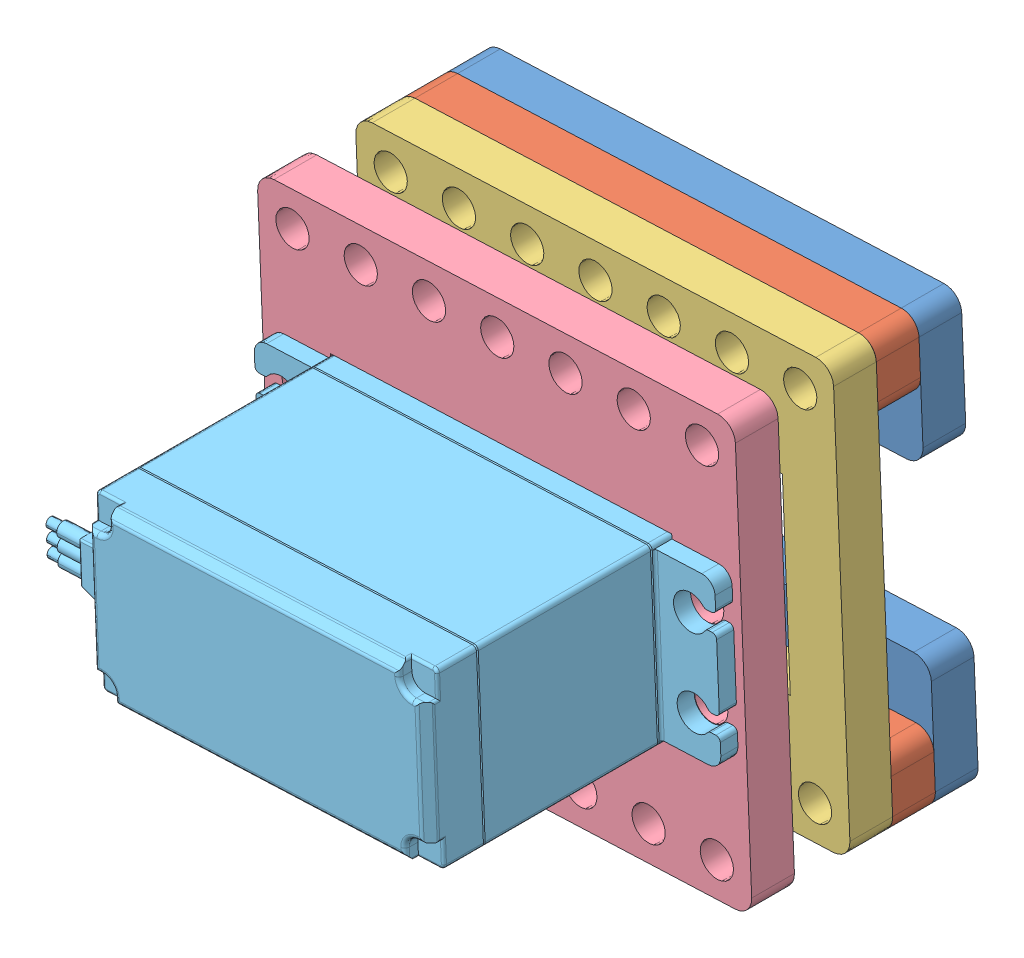
SolidWorks assembly assemblage ascenseur, configuration Default. Lengths in mm.
Overall size (58.03 51.54 55.5).
10 component instances, 8 part files, 27 mates.
Components (placement in the parent):
- 3mm support servo 5-1: 3mm support servo 5 [Default] at (55.3297 16.1146 111.995) x (-0.99911 -0.042175 0) z (0.042175 -0.99911 0) size (56 5 15)
- support servo 2-1: support servo 2 [Default] at (111.2799 18.4764 116.995) x (-0.99911 -0.042175 0) z (0.042175 -0.99911 0) size (56 5 8)
- X7 support servo 3-1: X7 support servo 3 [Default] at (55.3297 16.1146 121.995) x (-0.99911 -0.042175 0) z (0.042175 -0.99911 0) size (56 5 49.22)
- support servo 4-1: support servo 4 [Default] at (35.4252 -33.9894 133.495) x (0.99911 0.042175 0) z (-0.042175 0.99911 0) size (56 5 49.22)
- MG995.step-1: MG995.step [Default] at (84.3427 -7.2923 162.495) x (-0.99911 -0.042175 0) z (0 0 -1) size (55.5 20 44.5)
- 3mm support servo 5-2: 3mm support servo 5 [Default] at (57.4056 -33.0616 106.995) x (-0.99911 -0.042175 0) z (-0.042175 0.99911 0) size (56 5 15)
- new attach-1: new attach [Default] at (74.3516 -7.7141 116.995) x (0.990938 -0.134316 0) z (0 0 1) size (21 21 5.5)
- NEW ATTACH V4-1: NEW ATTACH V4 [Default] at (74.3516 -7.7141 111.995) x (-0.134316 -0.990938 0) z (0 0 1) size (24.86 25 5)
- support servo 2-3: support servo 2 [Default] at (57.4056 -33.0616 116.995) x (0.99911 0.042175 0) z (-0.042175 0.99911 0) size (56 5 8)
- NEW HORN-1: NEW HORN [Default] at (84.3427 -7.2923 117.995) x (-0.99911 -0.042175 0) z (0 0 -1) size (9.55 9.02 10)
Mates (geometry in assembly coordinates):
- Concentric2: concentric anti-aligned: cylinder of support servo 4-1 through (60.575 -13.3001 133.495) axis (0 0 -1) radius 1.95; cylinder of MG995.step-1 through (60.575 -13.3001 133.495) axis (0 0 1) radius 2
- Coincident3: coincident anti-aligned: plane of support servo 4-1 through (131.3465 17.3217 133.495) normal (0 0 1); plane of MG995.step-1 through (84.3427 -7.2923 133.495) normal (0 0 -1)
- Concentric12: concentric aligned: cylinder of MG995.step-1 through (74.3516 -7.7141 122.995) axis (0 0 1) radius 2; cylinder of new attach-1 through (74.3516 -7.7141 117.995) axis (0 0 1) radius 2.75
- Coincident30: coincident anti-aligned: plane of MG995.step-1 through (74.3516 -7.7141 117.995) normal (0 0 -1); plane of new attach-1 through (74.3516 -7.7141 117.995) normal (0 0 1)
- Concentric13: concentric aligned: cylinder of new attach-1 through (74.3516 -7.7141 120.495) axis (0 0 -1) radius 1.6; cylinder of NEW ATTACH V4-1 through (74.3516 -7.7141 116.995) axis (0 0 -1) radius 1.6
- Coincident34: coincident anti-aligned: plane of new attach-1 through (74.3516 -7.7141 116.995) normal (0 0 -1); plane of NEW ATTACH V4-1 through (74.3516 -7.7141 116.995) normal (0 0 1)
- Concentric15: concentric anti-aligned: cylinder of new attach-1 through (82.0204 -6.2307 115.495) axis (0 0 1) radius 1; cylinder of NEW ATTACH V4-1 through (82.0204 -6.2307 116.995) axis (0 0 -1) radius 1
- Coincident44: coincident aligned: plane of support servo 4-1 through (113.3558 -30.6998 138.495) normal (0.99911 0.042175 0); plane of support servo 2-3 through (113.2714 -28.7015 111.995) normal (0.99911 0.042175 0)
- Coincident45: coincident aligned: plane of support servo 2-1 through (111.3643 16.4782 111.995) normal (0.99911 0.042175 0); plane of support servo 4-1 through (113.3558 -30.6998 138.495) normal (0.99911 0.042175 0)
- Coincident46: coincident aligned: plane of support servo 2-1 through (111.3643 16.4782 111.995) normal (0.99911 0.042175 0); plane of support servo 3-1 through (111.3643 16.4782 116.995) normal (0.99911 0.042175 0)
- Coincident48: coincident anti-aligned: plane of support servo 2-1 through (57.581 10.2043 116.995) normal (0 0 1); plane of support servo 3-1 through (59.3194 -30.979 116.995) normal (0 0 -1)
- Coincident49: coincident aligned: plane of support servo 2-1 through (109.2817 18.3921 111.995) normal (-0.042175 0.99911 0); plane of support servo 3-1 through (109.2817 18.3921 116.995) normal (-0.042175 0.99911 0)
- Coincident50: coincident anti-aligned: plane of support servo 4-1 through (63.9388 1.855 133.495) normal (0.042175 -0.99911 0); plane of MG995.step-1 through (103.9032 3.5423 126.495) normal (-0.042175 0.99911 0)
- Coincident51: coincident anti-aligned: plane of 3mm support servo 5-1 through (57.8762 3.2106 111.995) normal (0 0 1); plane of support servo 2-1 through (57.581 10.2043 111.995) normal (0 0 -1)
- Coincident52: coincident aligned: plane of 3mm support servo 5-1 through (109.2817 18.3921 106.995) normal (-0.042175 0.99911 0); plane of support servo 2-1 through (109.2817 18.3921 111.995) normal (-0.042175 0.99911 0)
- Coincident53: coincident aligned: plane of 3mm support servo 5-1 through (55.4141 14.1164 106.995) normal (-0.99911 -0.042175 0); plane of support servo 2-1 through (55.4141 14.1164 111.995) normal (-0.99911 -0.042175 0)
- Coincident54: coincident anti-aligned: plane of 3mm support servo 5-2 through (58.8555 -19.9888 111.995) normal (0 0 1); plane of support servo 2-3 through (111.1045 -24.7895 111.995) normal (0 0 -1)
- Coincident55: coincident aligned: plane of 3mm support servo 5-2 through (111.3575 -30.7841 111.995) normal (0.042175 -0.99911 0); plane of support servo 2-3 through (59.4038 -32.9772 111.995) normal (0.042175 -0.99911 0)
- Coincident56: coincident aligned: plane of 3mm support servo 5-2 through (57.3212 -31.0633 111.995) normal (-0.99911 -0.042175 0); plane of support servo 2-3 through (57.3212 -31.0633 111.995) normal (-0.99911 -0.042175 0)
- Coincident57: coincident aligned: plane of NEW ATTACH V4-1 through (74.3516 -7.7141 111.995) normal (0 0 -1); plane of support servo 2-3 through (111.1045 -24.7895 111.995) normal (0 0 -1)
- Coincident58: coincident anti-aligned: plane of support servo 3-1 through (59.3194 -30.979 116.995) normal (0 0 -1); plane of support servo 2-3 through (111.1045 -24.7895 116.995) normal (0 0 1)
- Coincident59: coincident aligned: plane of support servo 3-1 through (111.3575 -30.7841 116.995) normal (0.042175 -0.99911 0); plane of support servo 2-3 through (59.4038 -32.9772 111.995) normal (0.042175 -0.99911 0)
- Coincident60: coincident aligned: plane of support servo 4-1 through (37.4234 -33.9051 128.495) normal (0.042175 -0.99911 0); plane of support servo 2-3 through (59.4038 -32.9772 111.995) normal (0.042175 -0.99911 0)
- InPlace1: in place: plane of MG995.step-1 through (74.3516 -7.7141 117.995) normal (0 0 -1); plane of ? through (0 0 117.995) normal (0 0 -1); moOrthogonalPlaneRef_w of MG995.step-1 through (74.3516 -7.7141 117.995) normal (0 0 -1); plane of ? through (0 0 117.995) normal (0 1 0); plane of MG995.step-1 through (74.3516 -7.7141 117.995) normal (0 0 -1); plane of ? through (0 0 117.995) normal (-1 0 0); plane of MG995.step-1 through (74.3516 -7.7141 117.995) normal (0 0 -1); unknown of NEW HORN-1
- Coincident61: coincident aligned: plane of MG995.step-1; plane of NEW HORN-1
- Coincident62: coincident aligned: moOrthogonalPlaneRef_w of MG995.step-1 through (84.3427 -7.2923 117.995) normal (-0.042175 0.99911 0); plane of NEW HORN-1 through (84.3427 -7.2923 117.995) normal (-0.042175 0.99911 0)
- Coincident63: coincident anti-aligned: moOrthogonalPlaneRef_w of MG995.step-1 through (84.3427 -7.2923 117.995) normal (0.99911 0.042175 0); plane of NEW HORN-1 through (84.3427 -7.2923 117.995) normal (-0.99911 -0.042175 0)
